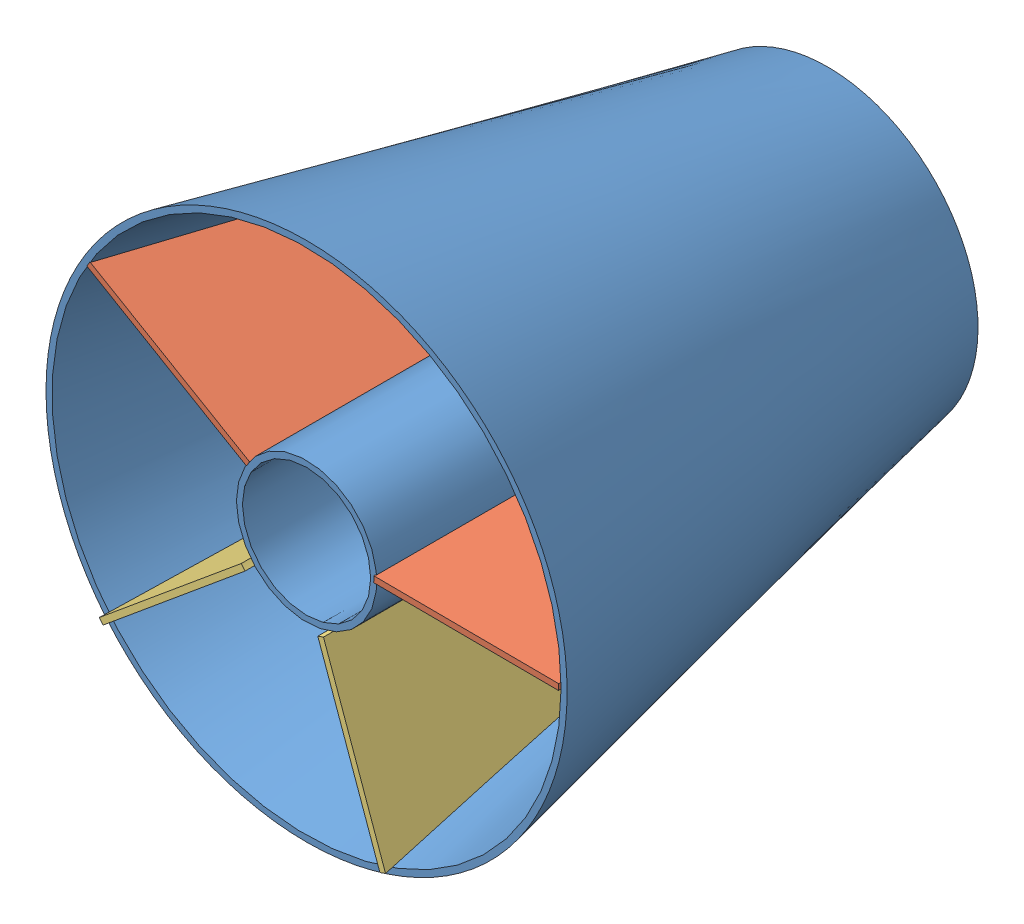
SolidWorks assembly Assem1, configuration Default. Lengths in mm.
Overall size (306.51 273.34 264.8).
4 component instances, 3 part files, 4 mates.
Components (placement in the parent):
- Part1-1: Part1 [Default] at (74.4276 180.7779 57.4746) size (265 263.73 260)
- Part2-1: Part2 [Default] at (108.8126 183.5818 61.3997) x (0.999984 -0.005705 -0.000305) z (-0.005705 -0.999984 0) size (92.26 257 3)
- Part3-1: Part3 [Default] at (74.4276 180.7779 122.2228) x (-0.005705 -0.999984 0) z (0 0 1) size (186.82 305.45 200.05)
- Part2-2: Part2 [Default] at (44.4578 198.3097 60.4746) x (-0.863159 0.504932 0) z (0.504932 0.863159 0) size (92.26 257 3)
Mates (geometry in assembly coordinates):
- Coincident7: coincident aligned: cylinder of Part1-1 through (74.4276 180.7779 317.4746) axis (0 0 -1) radius 35; circle of Part3-1
- Coincident8: coincident anti-aligned: plane of Part2-1 through (108.7955 180.5819 61.3997) normal (-0.005705 -0.999984 0); plane of Part3-1 through (74.4276 180.7779 37.2228) normal (0.005705 0.999984 0)
- Coincident9: coincident anti-aligned: plane of Part1-1 through (74.4276 180.7779 60.4746) normal (0 0 1); plane of Part2-2 through (45.9726 200.8992 60.4746) normal (0 0 -1)
- Coincident10: coincident anti-aligned: plane of Part3-1 through (74.4276 180.7779 37.2228) normal (0.504932 0.863159 0); plane of Part2-2 through (44.4578 198.3097 60.4746) normal (-0.504932 -0.863159 0)
